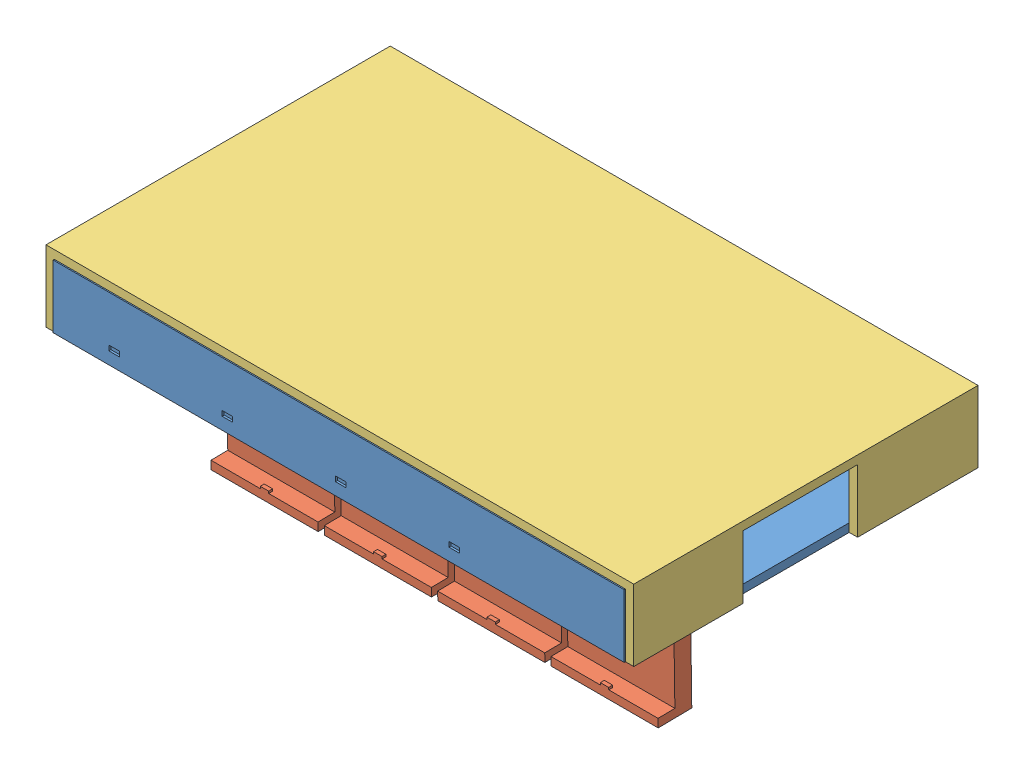
SolidWorks assembly whole, configuration 默认. Lengths in mm.
Overall size (140 62.08 82.29).
11 component instances, 4 part files, 9 mates.
Components (placement in the parent):
- main-1: main [默认] at (-23.515 1.412 142.0001) size (136 19 82)
- pcb-1: pcb [默认] at (3.7087 4.5397 142.3251) size (124.71 20 26.54) (hidden)
- cover-1: cover [默认] at (13.485 -0.588 142.0001) x (0 -0.464255 -0.885701) z (-1 0 0) size (45 8 25.5)
- cover-3: cover [默认] at (-13.515 -0.588 142.0001) x (0 -0.464255 -0.885701) z (-1 0 0) size (45 8 25.5)
- cover-4: cover [默认] at (-40.515 -0.588 142.0001) x (0 -0.464255 -0.885701) z (-1 0 0) size (45 8 25.5)
- cover-5: cover [默认] at (-67.515 -0.588 142.0001) x (0 -0.464255 -0.885701) z (-1 0 0) size (45 8 25.5)
- cover-18: cover [默认] at (-11.515 -0.588 142.0001) x (0 -0.999897 -0.014335) z (1 0 0) size (45 8 25.5)
- cover-19: cover [默认] at (-38.515 -0.588 142.0001) x (0 -0.999897 -0.014335) z (1 0 0) size (45 8 25.5)
- cover-20: cover [默认] at (-65.515 -0.588 142.0001) x (0 -0.999897 -0.014335) z (1 0 0) size (45 8 25.5)
- cover-21: cover [默认] at (-92.515 -0.588 142.0001) x (0 -0.999897 -0.014335) z (1 0 0) size (45 8 25.5)
- bottom-1: bottom [默认] at (-26.515 16.412 141.7084) size (140 17 82)
Mates (geometry in assembly coordinates):
- 平行1: parallel aligned: plane of main-1 through (-94.515 3.412 134.0001) normal (0 1 0); plane of pcb-1 through (3.7087 14.5397 142.3251) normal (0 1 0)
- 同心1: concentric aligned: circle of main-1; circle of cover-1
- 同心2: concentric aligned: circle of main-1; circle of cover-18
- 重合24: coincident anti-aligned: plane of main-1 through (-92.515 54.7004 181.0001) normal (1 0 0); plane of cover-21 through (-92.515 -0.588 142.0001) normal (-1 0 0)
- 重合25: coincident anti-aligned: plane of main-1 through (13.485 54.7004 132.0001) normal (-1 0 0); plane of cover-1 through (13.485 -0.588 142.0001) normal (1 0 0)
- 重合26: coincident anti-aligned: plane of main-1 through (-23.515 16.412 142.0001) normal (0 1 0); plane of bottom-1 through (-26.515 16.412 141.7084) normal (0 -1 0)
- 重合29: coincident aligned: line of main-1 through (41.485 1.412 183.0001) axis (0 0 -1); line of bottom-1 through (41.485 1.412 182.7084) axis (0 0 -1)
- 同心3: concentric anti-aligned: circle of main-1; circle of pcb-1
- 平行2: parallel anti-aligned: line of main-1 through (15.485 16.412 103.0001) axis (0 0 1); line of pcb-1 through (39.715 4.5397 157.0451) axis (0 0 -1)
